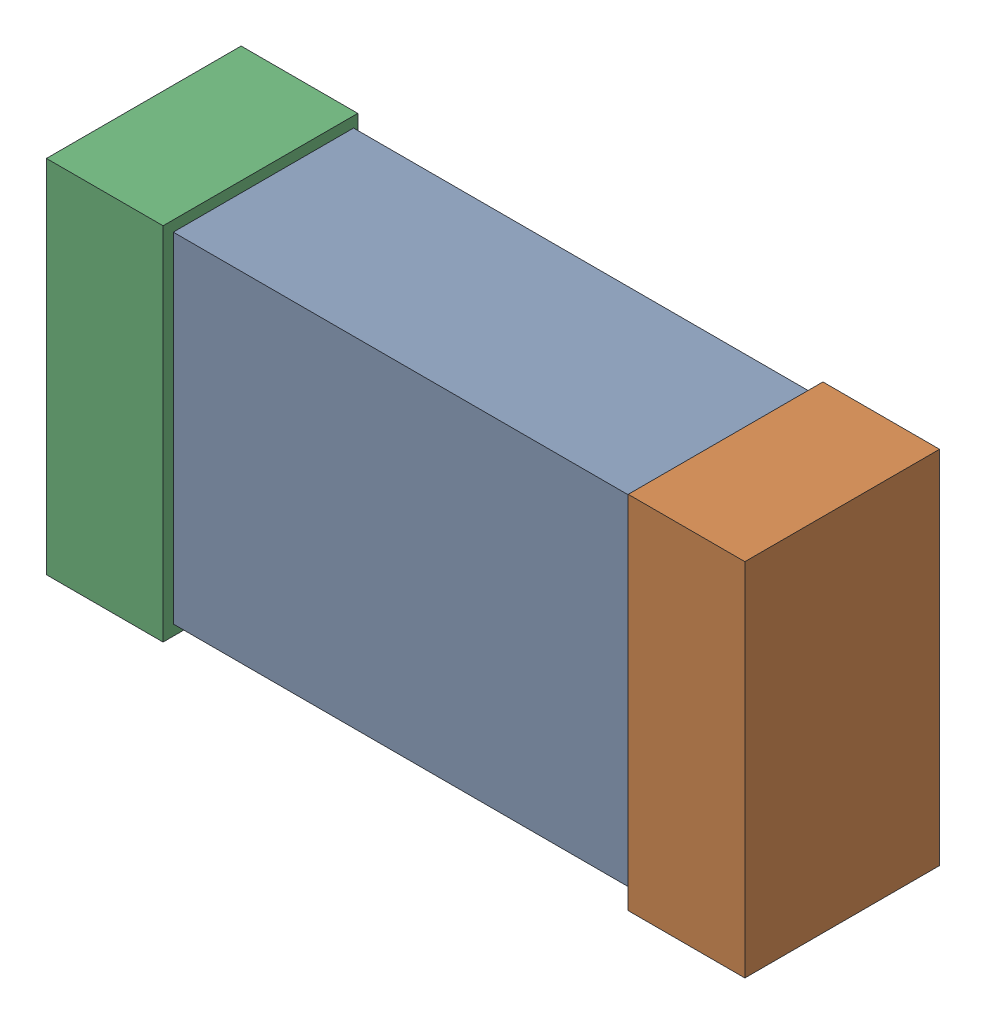
SolidWorks assembly R34, configuration Default. Lengths in mm.
Overall size (1.65 0.85 0.46).
6 component instances, 2 part files, 0 mates.
Components (placement in the parent):
- 432120720_3-1: 432120720_3 [Default] at (18.2499 32.7001 -0.8615) size (1.5 0.8 0.42)
  - Extruded (12)-1: Extruded (12) [Default] at origin size (1.5 0.8 0.42)
- 432120464_6-1: 432120464_6 [Default] at (18.9357 32.7001 -0.8715) size (0.28 0.85 0.46)
  - Extruded (11)-1: Extruded (11) [Default] at origin size (0.28 0.85 0.46)
- 432120464_7-1: 432120464_7 [Default] at (17.5642 32.7001 -0.8715) size (0.28 0.85 0.46)
  - Extruded (11)-1: Extruded (11) [Default] at origin size (0.28 0.85 0.46)
